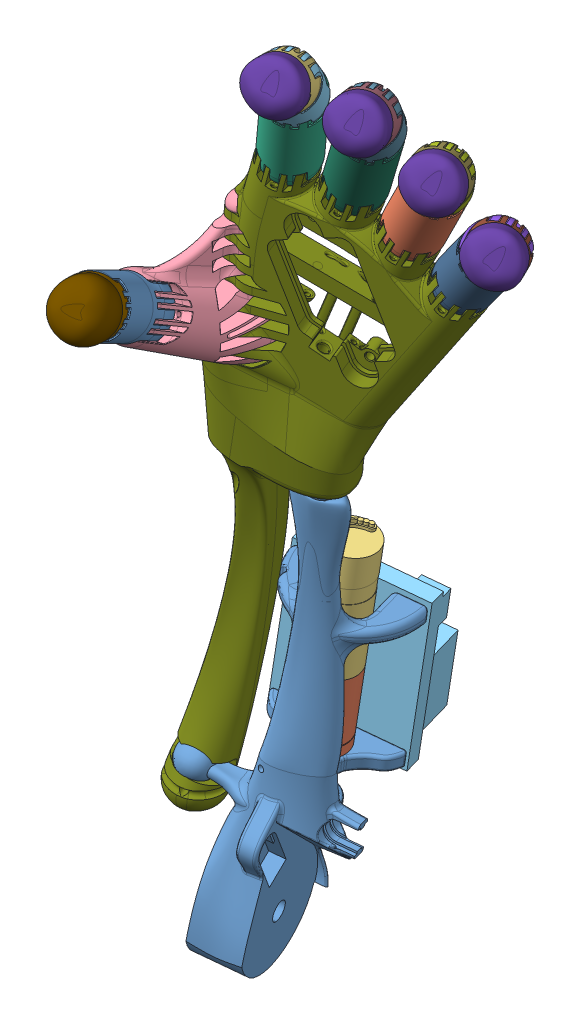
SolidWorks assembly a-unterarm-links, configuration Default. Lengths in mm.
Overall size (174.74 315.59 131.01).
28 component instances, 23 part files, 12 mates.
Components (placement in the parent):
- hand_links_0-1: hand_links_0 [linksStandard] at (170.9217 239.0976 138.4231) size (174.74 277.21 120.1)
  - p-daumen-seg-2-step-v01-2: p-daumen-seg-2-step-v01 [linksStandard] at (-105.8085 -71.1368 89.6014) x (-0.231233 0.848379 -0.476218) z (0.953119 0.09934 -0.285823) size (20.69 43.22 21.88)
  - p-ringfinger-seg-1-step-v02-2: p-ringfinger-seg-1-step-v02 [linksStandard] at (-82.2721 -87.3923 31.2992) x (0.834897 -0.441986 -0.328018) z (0.167049 -0.364366 0.916151) size (19.08 47.31 19.03)
  - p-zeigfinger-seg-3-step-v02-2: p-zeigfinger-seg-3-step-v02 [linksStandard] at (-122.5785 -47.8794 -30.4367) x (0.907236 -0.246273 -0.340988) z (-0.050565 -0.868652 0.492835) size (19.01 23.27 19)
  - p-daumen-seg-1-step-v01-2: p-daumen-seg-1-step-v01 [linksStandard] at (-100.474 -88.1528 56.8024) x (-0.144961 -0.741973 0.654571) z (-0.983441 0.035324 -0.177752) size (51 61.46 25.3)
  - p-zeigfinger-seg-2-step-v02-2: p-zeigfinger-seg-2-step-v02 [linksStandard] at (-137.8276 -111.3733 -25.0048) x (0.907236 -0.246273 -0.340988) z (0.095303 -0.66924 0.736909) size (19.2 35.59 19.73)
  - p-zeigfinger-seg-1-step-v02-2: p-zeigfinger-seg-1-step-v02 [linksStandard] at (-104.3344 -77.6629 39.9073) x (0.907236 -0.246273 -0.340988) z (0.229675 -0.389107 0.892101) size (19.08 48.86 19.03)
  - p-ringfinger-seg-2-step-v02-2: p-ringfinger-seg-2-step-v02 [linksStandard] at (-123.5586 -119.2331 -31.035) x (0.834897 -0.441986 -0.328018) z (-0.022395 -0.622741 0.782107) size (19.2 37.93 19.73)
  - p-kleinerfinger-seg-2-step-v02-2: p-kleinerfinger-seg-2-step-v02 [linksStandard] at (-101.3561 -110.3796 -16.5005) x (0.780209 -0.540448 -0.314944) z (-0.081347 -0.586882 0.805575) size (19.09 34.83 19.68)
  - p-daumen-seg-3-v01-2: p-daumen-seg-3-v01 [linksStandard] at (-101.2428 -59.0462 109.0287) x (0.509394 0.522602 0.68367) z (0.828884 -0.084496 -0.553002) size (28.23 20.09 20.4)
  - p-kleinerfinger-seg-1-step-v02-2: p-kleinerfinger-seg-1-step-v02 [linksStandard] at (-75.3128 -98.5287 27.5212) x (0.780209 -0.540448 -0.314944) z (0.135682 -0.345286 0.928638) size (19.08 41.2 19.03)
  - p-kleinerfinger-seg-3-step-v02-2: p-kleinerfinger-seg-3-step-v02 [linksStandard] at (-96.9388 -81.2121 -55.4508) x (0.780209 -0.540448 -0.314944) z (-0.288564 -0.757692 0.585349) size (18.67 21.72 17.82)
  - p-ringfinger-seg-3-step-v02-2: p-ringfinger-seg-3-step-v02 [linksStandard] at (-96.3832 -59.946 -41.5997) x (0.834897 -0.441986 -0.328018) z (-0.209139 -0.806005 0.55373) size (19.01 23.27 19)
  - p-mittelfinger-seg-3-step-v02-2: p-mittelfinger-seg-3-step-v02 [linksStandard] at (-88.7612 -32.6771 -4.2991) x (0.875864 -0.346025 -0.336346) z (-0.131494 -0.84177 0.523577) size (19.01 24.05 19)
  - p-mittelfinger-seg-2-step-v02-2: p-mittelfinger-seg-2-step-v02 [linksStandard] at (-85.001 -49.817 23.2747) x (0.875864 -0.346025 -0.336346) z (0.035235 -0.649287 0.759727) size (19.2 39.53 19.78)
  - p-mittelfinger-seg-1-step-v02-2: p-mittelfinger-seg-1-step-v02 [linksStandard] at (-109.2309 -113.1606 25.1963) x (0.875864 -0.346025 -0.336346) z (0.197714 -0.378491 0.904242) size (19.08 48.86 19.03)
  - p-handfläche-teil-2-v01-2: p-handfläche-teil-2-v01 [linksStandard] at (-93.4775 -100.6279 53.4744) x (-0.875864 0.346025 0.336346) z (-0.336346 0.062043 -0.939693) size (71.41 221.99 39.87)
  - p-fingerkuppe-12.4-1: p-fingerkuppe-12.4 [linksStandard] at (-9.4631 -23.5529 62.3085) x (0.780209 -0.540448 -0.314944) z (-0.288564 -0.757692 0.585349) size (17.55 9.03 17.93)
  - p-fingerkuppe-12.4-5: p-fingerkuppe-12.4 [linksStandard] at (-19.9026 -0.8036 73.3735) x (0.834897 -0.441986 -0.328018) z (-0.209139 -0.806005 0.55373) size (17.55 9.03 17.93)
  - p-fingerkuppe-12.4-6: p-fingerkuppe-12.4 [linksStandard] at (-37.0914 13.4349 82.8131) x (0.875864 -0.346025 -0.336346) z (-0.131494 -0.84177 0.523577) size (17.55 9.03 17.93)
  - p-fingerkuppe-12.4-7: p-fingerkuppe-12.4 [linksStandard] at (-60.7662 15.7541 88.0632) x (0.907236 -0.246273 -0.340988) z (-0.050565 -0.868652 0.492835) size (17.55 9.03 17.93)
  - p-fingerkuppe-18-1: p-fingerkuppe-18 [Standard] at (-90.1493 -47.6651 123.9175) x (0.231233 -0.848379 0.476218) z (-0.828884 0.084496 0.553002) size (18.01 12.53 19.06)
- p-ulna-v03_links-1: p-ulna-v03_links [01] at (45.2619 -246.1532 189.3694) x (0.954984 -0.1477 -0.257273) z (-0.255563 0.030771 -0.966303) size (70.58 164 44.35)
- z-ec-16-gp16-v01-1: z-ec-16-gp16-v01 [links01] at (79.9745 42.5426 173.859) x (0.150639 0.988553 -0.008361) z (0.657278 -0.106469 -0.74609) size (80.66 16 16)
  - z-gp16-401954-v01-1: z-gp16-401954-v01 [linksStandard] at origin size (38.5 16 16)
  - z-EC16-405813-v01-1: z-EC16-405813-v01 [links01] at (-6.1 0 0) size (48.26 16 16)
- p-motorpulley-2-v01-1: p-motorpulley-2-v01 [01] at (75.4929 13.1332 174.1077) x (-0.150639 -0.988553 0.008361) z (-0.113771 0.025737 0.993174) size (21 9 9)
- z-epos2-24-2-v01-1: z-epos2-24-2-v01 [01] at (76.9589 38.1239 165.202) x (-0.150639 -0.988553 0.008361) z (0.954984 -0.1477 -0.257273) size (55 19.6 40)
Mates (geometry in assembly coordinates):
- Tangent1: tangent anti-aligned: face of hand_links_0-1/p-handfläche-teil-2-v01-2; sphere of ?
- Tangent2: tangent anti-aligned: face of hand_links_0-1/p-handfläche-teil-2-v01-2; sphere of ?
- Tangent5: tangent anti-aligned: face of ?; sphere of ?
- Tangent6: tangent: face of hand_links_0-1/p-handfläche-teil-2-v01-2; sphere of p-ulna-v03_links-1
- Tangent7: tangent: face of hand_links_0-1/p-handfläche-teil-2-v01-2; sphere of p-ulna-v03_links-1
- Concentric1: concentric anti-aligned: cylinder of z-ec-16-gp16-v01-1/z-gp16-401954-v01-1 through (80.2644 44.4456 173.8429) axis (-0.150639 -0.988553 0.008361) radius 2; cylinder of p-motorpulley-2-v01-1 through (75.4929 13.1332 174.1077) axis (0.150639 0.988553 -0.008361) radius 2
- Coincident1: coincident anti-aligned: plane of z-ec-16-gp16-v01-1/z-gp16-401954-v01-1 through (75.4929 13.1332 174.1077) normal (-0.150639 -0.988553 0.008361); plane of p-motorpulley-2-v01-1 through (79.912 12.4642 174.6313) normal (0.150639 0.988553 -0.008361)
- Coincident2: coincident anti-aligned: plane of p-ulna-v03_links-1 through (71.2945 -7.5018 170.3698) normal (0.150639 0.988553 -0.008361); plane of p-motorpulley-2-v01-1 through (72.3295 -7.6265 174.2833) normal (-0.150639 -0.988553 0.008361)
- Concentric3: concentric aligned: cylinder of p-ulna-v03_links-1 through (75.3423 12.1446 174.1161) axis (0.150639 0.988553 -0.008361) radius 4.6; cylinder of p-motorpulley-2-v01-1 through (75.4929 13.1332 174.1077) axis (0.150639 0.988553 -0.008361) radius 4.5
- Concentric4: concentric anti-aligned: cylinder of p-ulna-v03_links-1 through (66.2414 63.5951 172.9871) axis (-0.255563 0.030771 -0.966303) radius 1.005; cylinder of z-epos2-24-2-v01-1 through (63.788 63.8905 163.7106) axis (0.255563 -0.030771 0.966303) radius 1.35
- Concentric5: concentric anti-aligned: cylinder of p-ulna-v03_links-1 through (89.7208 12.4066 165.1473) axis (-0.255563 0.030771 -0.966303) radius 1.005; cylinder of z-epos2-24-2-v01-1 through (87.2674 12.7021 155.8708) axis (0.255563 -0.030771 0.966303) radius 1.35
- Coincident3: coincident anti-aligned: plane of p-ulna-v03_links-1 through (77.4577 41.3974 165.1743) normal (-0.255563 0.030771 -0.966303); plane of z-epos2-24-2-v01-1 through (76.9589 38.1239 165.202) normal (0.255563 -0.030771 0.966303)
